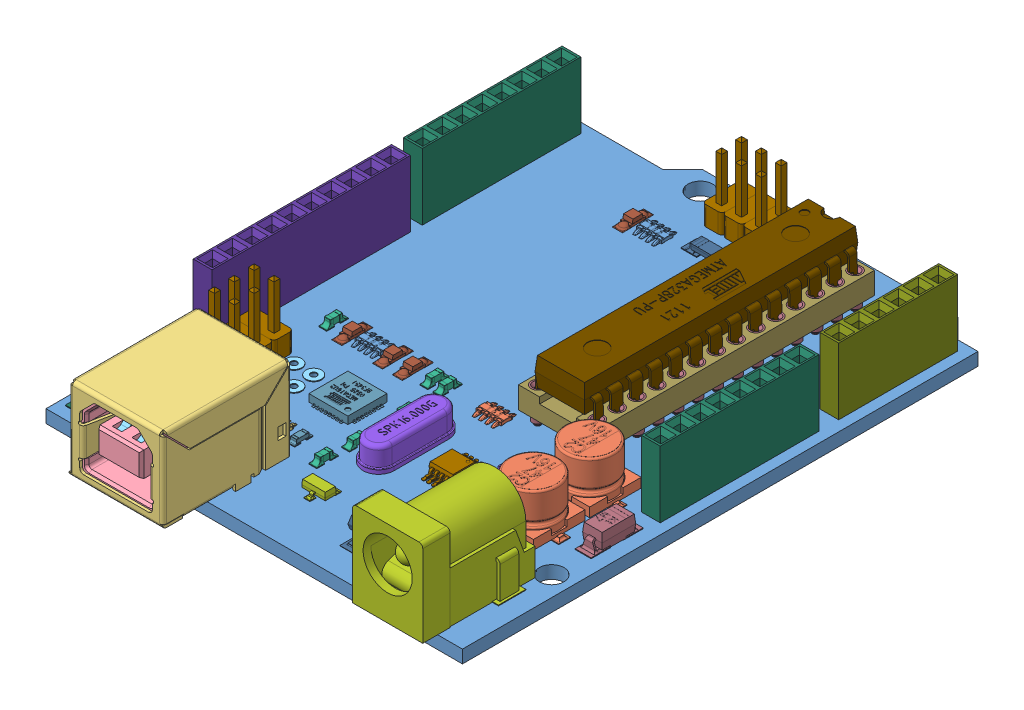
SolidWorks assembly arduino uno, configuration Default. Lengths in mm.
Overall size (53.34 15.25 74.93).
86 component instances, 34 part files, 0 mates.
Components (placement in the parent):
- arduino_uno_board-1: arduino_uno_board [Default] at origin size (53.34 1.65 68.58)
- 47uf CAP Dcase-1: 47uf CAP Dcase [Default] at (-9.4141 0 -18.4991) x (0 0 -1) z (1 0 0) size (6.6 5.81 8)
- USB type b-1: USB type b [Default] at (-38.02 0.43 6.35) size (13.72 15.2 16.5)
  - USB SHELL-1: USB SHELL [Default] at origin size (13.72 15.2 16.5)
  - USB core-1: USB core [Default] at origin size (11.3 10.68 15.75)
  - usb top contact-1: usb top contact [Default] at (1.25 6.09 -0.38) size (1 9.67 13.76)
  - usb btm contact-1: usb btm contact [Default] at (1.25 4.41 -0.38) size (1 6.84 11.76)
  - usb btm contact-2: usb btm contact [Default] at (-1.25 4.41 -0.38) size (1 6.84 11.76)
  - usb top contact-2: usb top contact [Default] at (-1.25 6.09 -0.38) size (1 9.67 13.76)
- power jack-1: power jack [Default] at (-7.675 0 1.905) size (11.2 15.2 15.9)
- 47uf CAP Dcase-2: 47uf CAP Dcase [Default] at (-9.4141 0 -25.7132) x (0 0 -1) z (1 0 0) size (6.6 5.81 8)
- crystal-1: crystal [Default] at (-26.162 0 -18.923) x (1 0 0) z (0 0 -1) size (4 5 11)
- 2pin_header__02-1: 2pin_header__02 [Default] at (-46.23 0 -15.75) size (5 11.75 2.54)
- nano - reg-1: nano - reg [Default] at (-17.399 0 -7.747) size (6.5 1.69 8.3)
- led-1: led [Default] at (-34.29 0 -27.94) x (0 0 1) z (-1 0 0) size (4 0.9 1.55)
- 2pin_header__02-2: 2pin_header__02 [Default] at (-30.43 0 -64.91) x (0 0 1) z (-1 0 0) size (5 11.75 2.54)
- dip28-1: dip28 [Default] at (-16.383 1.5 -46.355) x (0 0 -1) z (1 0 0) size (35.48 7.37 10.1)
  - dip28-1: dip28 [Default] at origin size (35.48 2.8 10.1)
  - dip socket pin-1: dip socket pin [Default] at (16.51 2.8 -3.81) size (1.7 7.37 1.7)
  - dip socket pin-2: dip socket pin [Default] at (16.51 2.8 3.81) size (1.7 7.37 1.7)
  - dip socket pin-3: dip socket pin [Default] at (13.97 2.8 -3.81) size (1.7 7.37 1.7)
  - dip socket pin-4: dip socket pin [Default] at (13.97 2.8 3.81) size (1.7 7.37 1.7)
  - dip socket pin-5: dip socket pin [Default] at (11.43 2.8 -3.81) size (1.7 7.37 1.7)
  - dip socket pin-6: dip socket pin [Default] at (11.43 2.8 3.81) size (1.7 7.37 1.7)
  - dip socket pin-7: dip socket pin [Default] at (8.89 2.8 -3.81) size (1.7 7.37 1.7)
  - dip socket pin-8: dip socket pin [Default] at (8.89 2.8 3.81) size (1.7 7.37 1.7)
  - dip socket pin-9: dip socket pin [Default] at (6.35 2.8 -3.81) size (1.7 7.37 1.7)
  - dip socket pin-10: dip socket pin [Default] at (6.35 2.8 3.81) size (1.7 7.37 1.7)
  - dip socket pin-11: dip socket pin [Default] at (3.81 2.8 -3.81) size (1.7 7.37 1.7)
  - dip socket pin-12: dip socket pin [Default] at (3.81 2.8 3.81) size (1.7 7.37 1.7)
  - dip socket pin-13: dip socket pin [Default] at (1.27 2.8 -3.81) size (1.7 7.37 1.7)
  - dip socket pin-14: dip socket pin [Default] at (1.27 2.8 3.81) size (1.7 7.37 1.7)
  - dip socket pin-15: dip socket pin [Default] at (-1.27 2.8 -3.81) size (1.7 7.37 1.7)
  - dip socket pin-16: dip socket pin [Default] at (-1.27 2.8 3.81) size (1.7 7.37 1.7)
  - dip socket pin-17: dip socket pin [Default] at (-3.81 2.8 -3.81) size (1.7 7.37 1.7)
  - dip socket pin-18: dip socket pin [Default] at (-3.81 2.8 3.81) size (1.7 7.37 1.7)
  - dip socket pin-19: dip socket pin [Default] at (-6.35 2.8 -3.81) size (1.7 7.37 1.7)
  - dip socket pin-20: dip socket pin [Default] at (-6.35 2.8 3.81) size (1.7 7.37 1.7)
  - dip socket pin-21: dip socket pin [Default] at (-8.89 2.8 -3.81) size (1.7 7.37 1.7)
  - dip socket pin-22: dip socket pin [Default] at (-8.89 2.8 3.81) size (1.7 7.37 1.7)
  - dip socket pin-23: dip socket pin [Default] at (-11.43 2.8 -3.81) size (1.7 7.37 1.7)
  - dip socket pin-24: dip socket pin [Default] at (-11.43 2.8 3.81) size (1.7 7.37 1.7)
  - dip socket pin-25: dip socket pin [Default] at (-13.97 2.8 -3.81) size (1.7 7.37 1.7)
  - dip socket pin-26: dip socket pin [Default] at (-13.97 2.8 3.81) size (1.7 7.37 1.7)
  - dip socket pin-27: dip socket pin [Default] at (-16.51 2.8 -3.81) size (1.7 7.37 1.7)
  - dip socket pin-28: dip socket pin [Default] at (-16.51 2.8 3.81) size (1.7 7.37 1.7)
- 2pin_header__02-3: 2pin_header__02 [Default] at (-27.89 0 -64.91) x (0 0 1) z (-1 0 0) size (5 11.75 2.54)
- 2pin_header__02-4: 2pin_header__02 [Default] at (-25.35 0 -64.91) x (0 0 1) z (-1 0 0) size (5 11.75 2.54)
- 2pin_header__02-5: 2pin_header__02 [Default] at (-46.23 0 -18.29) size (5 11.75 2.54)
- 2pin_header__02-6: 2pin_header__02 [Default] at (-46.23 0 -20.83) size (5 11.75 2.54)
- atmega16u2-1: atmega16u2 [Default] at (-34.671 0.06 -20) x (1 0 0) z (0 0 -1) size (5.5 1.01 5.5)
- led-2: led [Default] at (-36.83 0 -27.94) x (0 0 1) z (-1 0 0) size (4 0.9 1.55)
- led-3: led [Default] at (-42.037 0 -27.94) x (0 0 1) z (-1 0 0) size (4 0.9 1.55)
- led-4: led [Default] at (-36.576 0 -58.42) x (0 0 1) z (-1 0 0) size (4 0.9 1.55)
- 8 PORT HEADER-1: 8 PORT HEADER [Default] at (-50.8 0 -45.72) x (0 0 -1) z (1 0 0) size (20.32 10.51 2.41)
- 8 PORT HEADER-2: 8 PORT HEADER [Default] at (-2.54 0 -27.94) x (0 0 -1) z (1 0 0) size (20.32 10.51 2.41)
- 6 PORT HEADER-1: 6 PORT HEADER [Default] at (-2.54 0 -50.8) x (0 0 -1) z (1 0 0) size (15.24 10.51 2.41)
- 10 PORT HEADER-1: 10 PORT HEADER [Default] at (-50.8 0 -18.796) x (0 0 -1) z (1 0 0) size (25.4 10.51 2.41)
- ATMEL328P-1: ATMEL328P [Default] at (-16.383 4.3 -46.355) x (0 0 -1) z (1 0 0) size (35 7.27 7.87)
- 102 RESISTOR PACK-1: 102 RESISTOR PACK [Default] at (-33.782 0 -58.42) size (3.2 0.51 3)
- 102 RESISTOR PACK-2: 102 RESISTOR PACK [Default] at (-39.37 0 -27.94) size (3.2 0.51 3)
- 103 RESISTOR PACK-1: 103 RESISTOR PACK [Default] at (-23.876 0 -27.94) size (3.2 0.51 3)
- 220 RESISTOR PACK-1: 220 RESISTOR PACK [Default] at (-36.83 0 -12.827) size (3.2 0.51 3)
- 16mhz crystal - measured-1: 16mhz crystal - measured [Default] at (-24.892 0 -41.275) x (0 0 -1) z (1 0 0) size (3.4 0.8 2.01)
- PADS001-1: PADS001 [Default] at (-39.878 0.1 -18.288) x (-1 0 0) z (0 0 1) size (4.54 0.1 4.54)
- 603 cap on pad-1: 603 cap on pad [Default] at (-44.45 0 -27.94) x (0 0 -1) z (1 0 0) size (2.76 0.9 1.02)
- ssot3-1: ssot3 [Default] at (-26.5 0 -8.128) x (-1 0 0) z (0 0 -1) size (3 1.13 3.09)
- 603 cap on pad-2: 603 cap on pad [Default] at (-29.845 0 -27.94) x (0 0 -1) z (1 0 0) size (2.76 0.9 1.02)
- 603 cap on pad-3: 603 cap on pad [Default] at (-31.496 0 -27.94) x (0 0 -1) z (1 0 0) size (2.76 0.9 1.02)
- lmv358-1: lmv358 [Default] at (-15.24 0 -21.971) x (0 0 -1) z (1 0 0) size (3.7 1.4 2.9)
- 603 cap on pad-4: 603 cap on pad [Default] at (-15.24 0 -18.415) size (2.76 0.9 1.02)
- 603 cap on pad-5: 603 cap on pad [Default] at (-29.845 0 -12.065) x (0 0 1) z (-1 0 0) size (2.76 0.9 1.02)
- 603 cap on pad-6: 603 cap on pad [Default] at (-29.591 0 -22.352) x (0 0 1) z (-1 0 0) size (2.76 0.9 1.02)
- 603 cap on pad-7: 603 cap on pad [Default] at (-29.591 0 -16.002) x (0 0 1) z (-1 0 0) size (2.76 0.9 1.02)
- 603 cap on pad-8: 603 cap on pad [Default] at (-41.91 0 -12.7) x (0 0 1) z (-1 0 0) size (2.76 0.9 1.02)
- lp2985dgkr-1: lp2985dgkr [Default] at (-20.32 0 -19.05) x (0 0 -1) z (1 0 0) size (5.85 1.1 3)
- cd1206 diode-1: cd1206 diode [Default] at (-27.94 0 -59.436) x (0 0 -1) z (1 0 0) size (2.08 0.96 5)
- cd1206 diode-2: cd1206 diode [Default] at (-46.228 0 -13.081) x (0 0 1) z (-1 0 0) size (2.08 0.96 5)
- 603 resistor-1: 603 resistor [Default] at (-29.591 0 -19.05) x (0 0 1) z (-1 0 0) size (2.36 0.62 1.04)
- blm21-1: blm21 [Default] at (-45.085 0 -7.62) x (0 0 -1) z (1 0 0) size (2.78 0.95 1.32)
- m7 diode-1: m7 diode [Default] at (-2.794 0 -21.59) x (0 0 -1) z (1 0 0) size (6.66 2.35 2.5)
- MLC0603-1: MLC0603 [Default] at (-33.655 0 -12.827) x (0 0 -1) z (1 0 0) size (2.36 0.6 1.04)
- MLC0603-2: MLC0603 [Default] at (-39.37 0 -12.827) x (0 0 -1) z (1 0 0) size (2.36 0.6 1.04)
- RESET BUTTON-1: RESET BUTTON [Default] at (-49.403 0 -6.35) size (6.2 3.1 9.6)
  - RESET CORE-1: RESET CORE [Default] at (0 0.1 0) x (-1 0 0) z (0 0 -1) size (6.2 3.1 9.6)
  - RESET-1: RESET [Default] at (0 0.1 0) x (0 0 1) z (-1 0 0) size (7.3 2 6.2)
